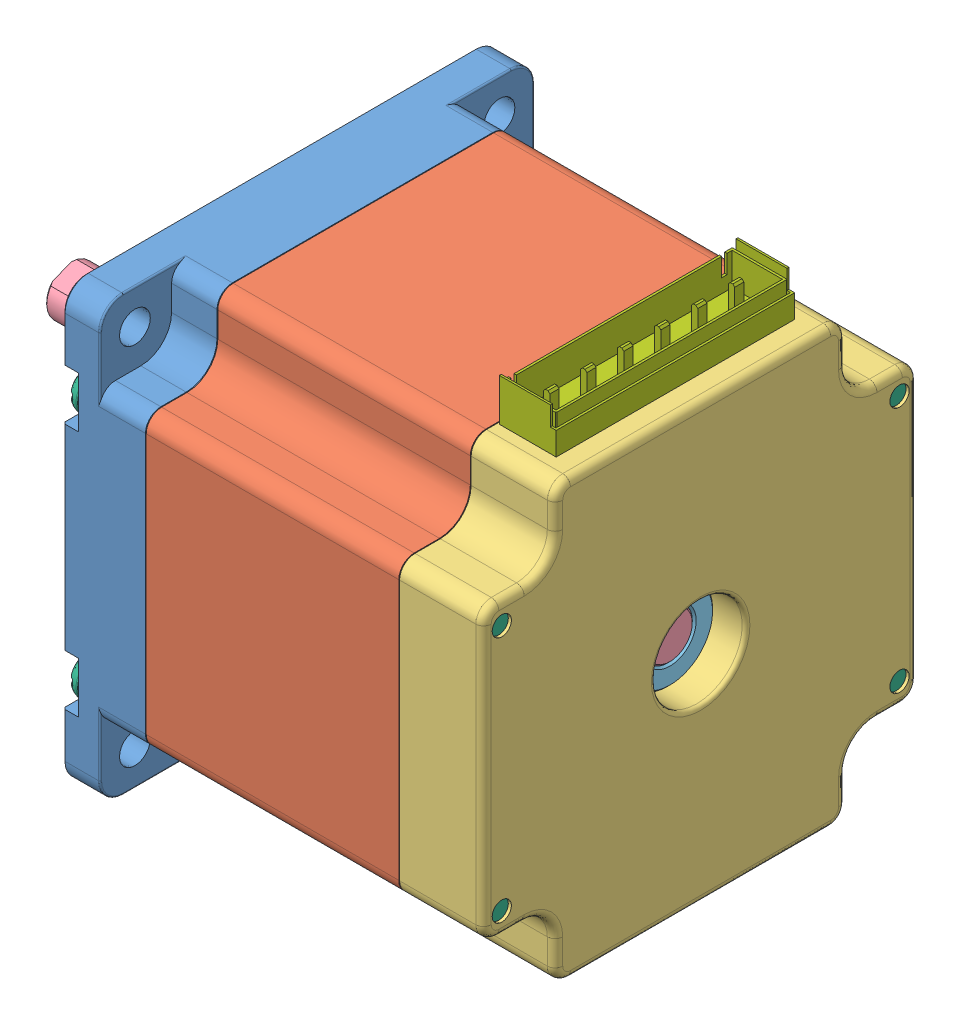
SolidWorks assembly NEMA_235628-6.35_s, configuration Default. Lengths in mm.
Overall size (82 61.9 56.65).
11 component instances, 7 part files, 22 mates.
Components (placement in the parent):
- Nema2356_top-1: Nema2356_top [Default] at (-25.5081 -82.6274 143.9932) size (12.4 56.4 56.4)
- Nema2356_middle-1: Nema2356_middle [Default] at (-14.7081 17.769 14.044) size (32.8 56.4 56.4)
- Nema2356_bottom-1: Nema2356_bottom [Default] at (18.0919 -112.7781 -165.2225) size (11 56.4 56.4)
- Nema2356_axis-1: Nema2356_axis [Default] at (-52.9081 -12.2004 -20.8718) x (1 0 0) z (0 -0.367241 0.930126) size (78 6.35 6.35)
- Nema2356_gultnis-1: Nema2356_gultnis [Default] at (-25.7081 -12.2004 -20.8718) x (1 0 0) z (0 0.415119 0.909767) size (3 11.6 11.6)
- Nema2356_gultnis-2: Nema2356_gultnis [Default] at (22.0919 -12.2004 -20.8718) size (3 11.6 11.6)
- Nema2356_screv-1: Nema2356_screv [Default] at (-13.1349 -28.2433 4.9528) size (54.1 5 5)
- Nema2356_screv-2: Nema2356_screv [Default] at (-13.1349 3.8425 4.9528) size (54.1 5 5)
- Nema2356_screv-3: Nema2356_screv [Default] at (-13.1349 -28.2433 -46.6964) size (54.1 5 5)
- Nema2356_screv-4: Nema2356_screv [Default] at (-13.1349 3.8425 -46.6964) size (54.1 5 5)
- Nema2356_contact-1: Nema2356_contact [Default] at (21.7519 15.9996 -20.8718) size (7.63 5.5 30.97)
Mates (geometry in assembly coordinates):
- Width1: width anti-aligned: plane of Nema2356_middle-1 through (18.0919 15.9996 -37.7818) normal (0 1 0); plane of Nema2356_middle-1 through (18.0919 -40.4004 -3.9618) normal (0 -1 0); plane of Nema2356_top-1 through (-20.7081 -40.4004 -46.0718) normal (0 -1 0); plane of Nema2356_top-1 through (-20.7081 15.9996 -46.0718) normal (0 1 0)
- Width2: width aligned: plane of Nema2356_middle-1 through (18.0919 4.7096 7.3282) normal (0 0 1); plane of Nema2356_middle-1 through (18.0919 -29.1104 -49.0718) normal (0 0 -1); plane of Nema2356_top-1 through (-20.7081 -37.4004 7.3282) normal (0 0 1); plane of Nema2356_top-1 through (-20.7081 -37.4004 -49.0718) normal (0 0 -1)
- Coincident2: coincident anti-aligned: plane of Nema2356_top-1 through (-14.7081 4.7096 5.3282) normal (1 0 0); plane of Nema2356_middle-1 through (-14.7081 4.7096 5.3282) normal (-1 0 0)
- Width3: width anti-aligned: plane of Nema2356_bottom-1 through (29.0919 15.9996 -37.7818) normal (0 1 0); plane of Nema2356_bottom-1 through (29.0919 -40.4004 -3.9618) normal (0 -1 0); plane of Nema2356_middle-1 through (18.0919 -40.4004 -3.9618) normal (0 -1 0); plane of Nema2356_middle-1 through (18.0919 15.9996 -37.7818) normal (0 1 0)
- Width4: width anti-aligned: plane of Nema2356_bottom-1 through (29.0919 4.7096 7.3282) normal (0 0 1); plane of Nema2356_bottom-1 through (29.0919 -29.1104 -49.0718) normal (0 0 -1); plane of Nema2356_middle-1 through (18.0919 -29.1104 -49.0718) normal (0 0 -1); plane of Nema2356_middle-1 through (18.0919 4.7096 7.3282) normal (0 0 1)
- Coincident3: coincident anti-aligned: plane of Nema2356_middle-1 through (18.0919 4.7096 5.3282) normal (1 0 0); plane of Nema2356_bottom-1 through (18.0919 4.7096 5.3282) normal (-1 0 0)
- Concentric1: concentric anti-aligned: cylinder of Nema2356_bottom-1 through (18.0919 -12.2004 -20.8718) axis (1 0 0) radius 5.9; cylinder of Nema2356_axis-1 through (25.0919 -12.2004 -20.8718) axis (-1 0 0) radius 3.175
- Distance1: distance = 4 mm aligned: plane of Nema2356_axis-1 through (25.0919 -12.2004 -20.8718) normal (1 0 0); plane of Nema2356_bottom-1 through (29.0919 4.7096 5.3282) normal (1 0 0)
- Concentric2: concentric aligned: cylinder of Nema2356_axis-1 through (25.0919 -12.2004 -20.8718) axis (-1 0 0) radius 3.175; cylinder of Nema2356_gultnis-1 through (-22.7081 -12.2004 -20.8718) axis (-1 0 0) radius 3.17
- Distance2: distance = 0.2 mm aligned: plane of Nema2356_gultnis-1 through (-25.7081 -12.2004 -20.8718) normal (-1 0 0); plane of Nema2356_top-1 through (-25.5081 12.9996 -46.0718) normal (-1 0 0)
- Concentric3: concentric anti-aligned: cylinder of Nema2356_bottom-1 through (18.0919 -12.2004 -20.8718) axis (1 0 0) radius 5.9; cylinder of Nema2356_gultnis-2 through (25.0919 -12.2004 -20.8718) axis (-1 0 0) radius 3.17
- Coincident6: coincident aligned: plane of Nema2356_axis-1 through (25.0919 -12.2004 -20.8718) normal (1 0 0); plane of Nema2356_gultnis-2 through (25.0919 -12.2004 -20.8718) normal (1 0 0)
- Concentric4: concentric aligned: cylinder of Nema2356_top-1 through (-14.7081 -28.2433 4.9528) axis (-1 0 0) radius 1.52; cylinder of Nema2356_screv-1 through (-70.1182 -28.2433 4.9528) axis (-1 0 0) radius 1.5
- Coincident7: coincident anti-aligned: plane of Nema2356_top-1 through (-23.5081 -28.2433 4.9528) normal (-1 0 0); plane of Nema2356_screv-1 through (-23.5081 -28.2433 3.4528) normal (1 0 0)
- Concentric6: concentric aligned: cylinder of Nema2356_top-1 through (-14.7081 3.8425 4.9528) axis (-1 0 0) radius 1.52; cylinder of Nema2356_screv-2 through (-70.1182 3.8425 4.9528) axis (-1 0 0) radius 1.5
- Coincident8: coincident aligned: plane of Nema2356_screv-1 through (-25.3081 -28.2433 4.0528) normal (-1 0 0); plane of Nema2356_screv-2 through (-25.3081 3.8425 4.0528) normal (-1 0 0)
- Concentric7: concentric aligned: cylinder of Nema2356_top-1 through (-14.7081 3.8425 -46.6964) axis (-1 0 0) radius 1.52; cylinder of Nema2356_screv-4 through (-70.1182 3.8425 -46.6964) axis (-1 0 0) radius 1.5
- Concentric8: concentric aligned: cylinder of Nema2356_top-1 through (-14.7081 -28.2433 -46.6964) axis (-1 0 0) radius 1.52; cylinder of Nema2356_screv-3 through (-70.1182 -28.2433 -46.6964) axis (-1 0 0) radius 1.5
- Coincident9: coincident aligned: plane of Nema2356_screv-2 through (-25.3081 3.8425 4.0528) normal (-1 0 0); plane of Nema2356_screv-4 through (-25.3081 3.8425 -47.5964) normal (-1 0 0)
- Coincident10: coincident aligned: plane of Nema2356_screv-1 through (-25.3081 -28.2433 4.0528) normal (-1 0 0); plane of Nema2356_screv-3 through (-25.3081 -28.2433 -47.5964) normal (-1 0 0)
- Width5: width anti-aligned: plane of Nema2356_contact-1 through (18.1919 20.4996 -5.8718) normal (0 0 1); plane of Nema2356_contact-1 through (18.1919 20.4996 -35.8718) normal (0 0 -1); plane of Nema2356_bottom-1 through (29.0919 10.7096 -39.7818) normal (0 0 -1); plane of Nema2356_bottom-1 through (29.0919 13.9996 -1.9618) normal (0 0 1)
- Coincident11: coincident aligned: line of Nema2356_bottom-1 through (18.1919 15.9996 -37.7818) axis (0 0 1); line of Nema2356_contact-1 through (18.1919 15.9996 -35.7718) axis (0 0 1)
